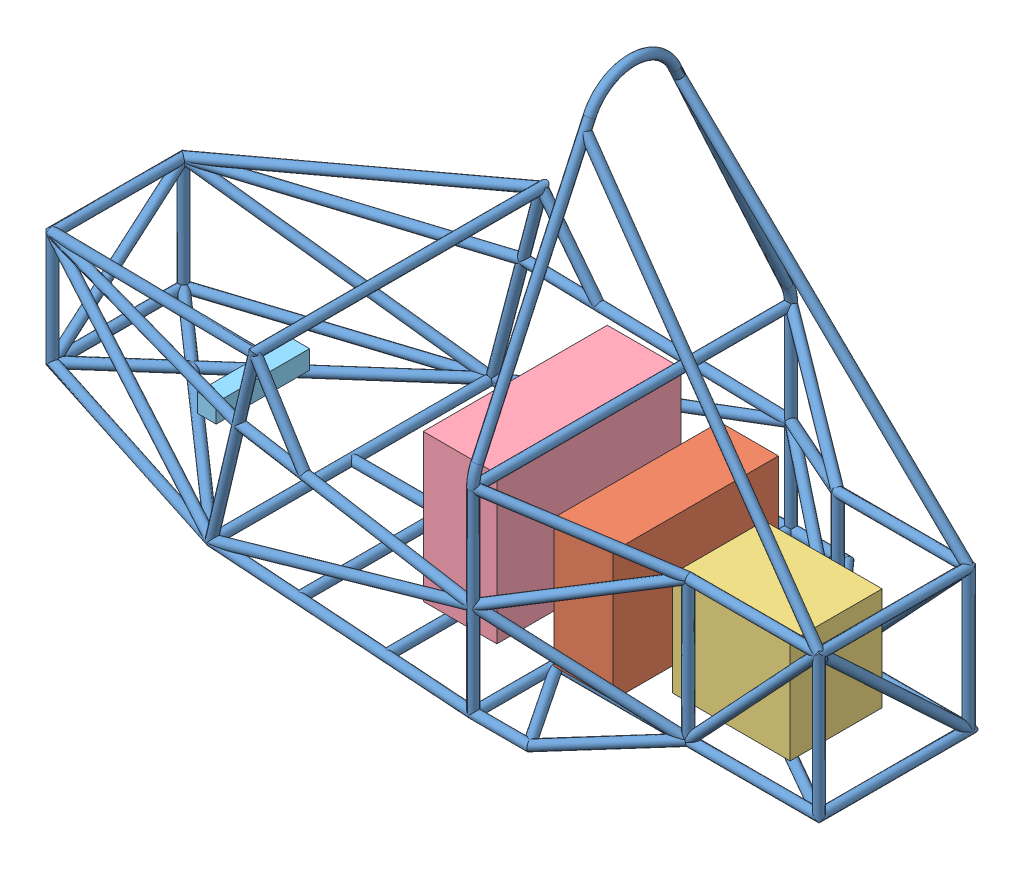
SolidWorks assembly Astra Assem, configuration Default. Lengths in mm.
Overall size (2137.39 1351.01 1066.8).
5 component instances, 5 part files, 12 mates.
Components (placement in the parent):
- Astra Base1.0-1: Astra Base1.0 [Default<As Welded>] at (834.9474 525.5633 1642.7549) size (2137.39 1351.01 1066.8)
- battery1-1: battery1 [Default] at (1223.5474 713.2633 1642.7549) x (0 0 1) z (-1 0 0) size (450 350 160)
- motor-1: motor [Default] at (1447.0474 678.2633 1769.7549) x (0 0 -1) z (1 0 0) size (250 280 320)
- driver-1: driver [Default] at (733.3474 738.2633 1642.7549) size (200 400 500)
- rack and pinion-1: rack and pinion [Default] at (-3.2526 576.3633 1642.7549) x (0 0 1) z (0 1 0) size (254 50.8 50.8)
Mates (geometry in assembly coordinates):
- Distance1: distance = 12.7 mm anti-aligned: plane of battery1-1 through (1063.5474 713.2633 1642.7549) normal (-1 0 0); plane of Astra Base1.0-1 through (1050.8474 525.5633 1642.7549) normal (1 0 0)
- Distance2: distance = 12.7 mm: plane of battery1-1 through (1063.5474 538.2633 1417.7549) normal (0 -1 0); line of Astra Base1.0-1 through (1050.8474 525.5633 1439.5549) axis (0 0 1)
- Coincident7: coincident aligned: plane of Astra Base1.0-1 through (834.9474 525.5633 1642.7549) normal (0 0 1); plane of battery1-1 through (1223.5474 713.2633 1642.7549) normal (0 0 1)
- Distance5: distance = 63.5 mm anti-aligned: plane of motor-1 through (1287.0474 818.2633 1519.7549) normal (-1 0 0); plane of battery1-1 through (1223.5474 713.2633 1642.7549) normal (1 0 0)
- Coincident10: coincident aligned: plane of battery1-1 through (1063.5474 538.2633 1417.7549) normal (0 -1 0); plane of motor-1 through (1607.0474 538.2633 1519.7549) normal (0 -1 0)
- Distance6: distance = 127 mm anti-aligned: plane of Astra Base1.0-1 through (834.9474 525.5633 1642.7549) normal (0 0 1); plane of motor-1 through (1447.0474 678.2633 1769.7549) normal (0 0 -1)
- Distance9: distance = 101.6 mm anti-aligned: plane of Astra Base1.0-1 through (834.9474 525.5633 1642.7549) normal (1 0 0); plane of driver-1 through (733.3474 738.2633 1642.7549) normal (-1 0 0)
- Distance7: distance = 12.7 mm anti-aligned: plane of Astra Base1.0-1 through (834.9474 525.5633 1642.7549) normal (0 1 0); plane of driver-1 through (933.3474 538.2633 1892.7549) normal (0 -1 0)
- Distance8: distance = 250 mm anti-aligned: plane of Astra Base1.0-1 through (834.9474 525.5633 1642.7549) normal (0 0 1); plane of driver-1 through (933.3474 938.2633 1392.7549) normal (0 0 -1)
- Distance10: distance = 685.8 mm anti-aligned: plane of rack and pinion-1 through (47.5474 576.3633 1642.7549) normal (1 0 0); plane of driver-1 through (733.3474 738.2633 1642.7549) normal (-1 0 0)
- Distance11: distance = 25.4 mm anti-aligned: plane of rack and pinion-1 through (47.5474 550.9633 1515.7549) normal (0 -1 0); plane of Astra Base1.0-1 through (834.9474 525.5633 1642.7549) normal (0 1 0)
- Distance12: distance = 127 mm anti-aligned: plane of rack and pinion-1 through (47.5474 550.9633 1515.7549) normal (0 0 -1); plane of Astra Base1.0-1 through (834.9474 525.5633 1642.7549) normal (0 0 1)
